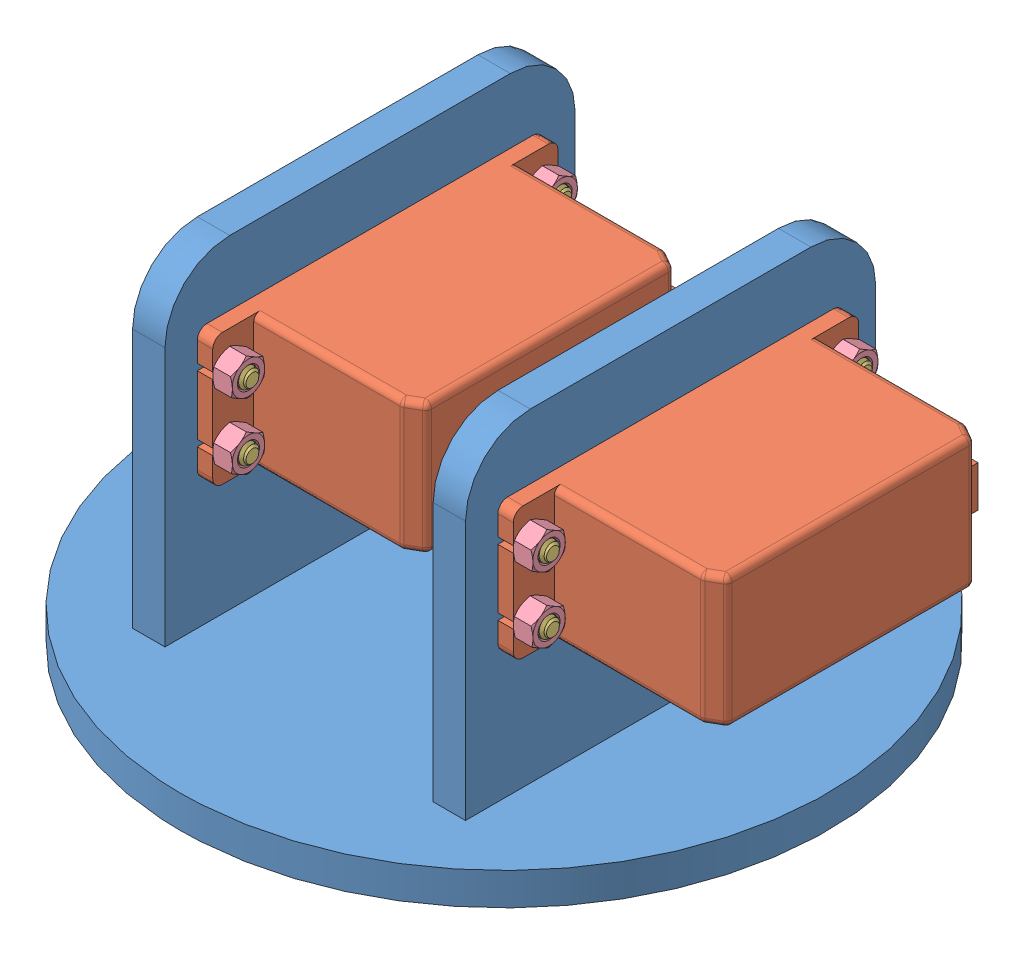
SolidWorks assembly Assem2, configuration Default. Lengths in mm.
Overall size (103.47 55 100).
19 component instances, 4 part files, 54 mates.
Components (placement in the parent):
- Part1-1: Part1 [Default] at origin size (100 55 100)
- Motor2-1: Motor2 [Default] at (-33.5143 32.34 10.1954) x (0 1 0) z (0 0 1) size (20.32 45.1 53.29)
- Motor2-2: Motor2 [Default] at (12.8743 32.34 10.1954) x (0 1 0) z (0 0 1) size (20.32 45.1 53.29)
- straf3_dolg11-1: straf3_dolg11 [Default] at (-25.6943 37.42 -24.12) x (-1 0 0) z (0 0 -1) size (14.31 5.77 5)
- straf3_dolg11-2: straf3_dolg11 [Default] at (-25.6943 27.26 -24.12) x (-1 0 0) z (0 0 -1) size (14.31 5.77 5)
- straf3_dolg11-3: straf3_dolg11 [Default] at (-25.6943 37.42 24.14) x (-1 0 0) z (0 0 -1) size (14.31 5.77 5)
- straf3_dolg11-4: straf3_dolg11 [Default] at (-25.6943 27.26 24.14) x (-1 0 0) z (0 0 -1) size (14.31 5.77 5)
- straf3_dolg11-5: straf3_dolg11 [Default] at (20.6943 27.26 -24.12) x (-1 0 0) z (0 0 -1) size (14.31 5.77 5)
- straf3_dolg11-6: straf3_dolg11 [Default] at (20.6943 37.42 -24.12) x (-1 0 0) z (0 0 -1) size (14.31 5.77 5)
- straf3_dolg11-7: straf3_dolg11 [Default] at (20.6943 27.26 24.14) x (-1 0 0) z (0 0 -1) size (14.31 5.77 5)
- straf3_dolg11-8: straf3_dolg11 [Default] at (20.6943 37.42 24.14) x (-1 0 0) z (0 0 -1) size (14.31 5.77 5)
- navrtka1-1: navrtka1 [Default] at (-16.8143 37.42 -24.12) x (0 0 -1) z (1 0 0) size (5.57 5.77 3)
- navrtka1-2: navrtka1 [Default] at (-16.8143 27.26 -24.12) x (0 0 -1) z (1 0 0) size (5.57 5.77 3)
- navrtka1-3: navrtka1 [Default] at (-16.8143 27.26 24.14) x (0 0 -1) z (1 0 0) size (5.57 5.77 3)
- navrtka1-4: navrtka1 [Default] at (-16.8143 37.42 24.14) x (0 0 -1) z (1 0 0) size (5.57 5.77 3)
- navrtka1-5: navrtka1 [Default] at (29.5743 37.42 -24.12) x (0 0 -1) z (1 0 0) size (5.57 5.77 3)
- navrtka1-6: navrtka1 [Default] at (29.5743 27.26 -24.12) x (0 0 -1) z (1 0 0) size (5.57 5.77 3)
- navrtka1-7: navrtka1 [Default] at (29.5743 37.42 24.14) x (0 0 -1) z (1 0 0) size (5.57 5.77 3)
- navrtka1-8: navrtka1 [Default] at (29.5743 27.26 24.14) x (0 0 -1) z (1 0 0) size (5.57 5.77 3)
Mates (geometry in assembly coordinates):
- Concentric1: concentric aligned: cylinder of Part1-1 through (-20.6943 27.26 -24.12) axis (1 0 0) radius 1.5; cylinder of Motor2-1 through (-20.6943 27.26 -24.12) axis (1 0 0) radius 1.5
- Concentric2: concentric aligned: cylinder of Part1-1 through (-20.6943 37.42 24.14) axis (1 0 0) radius 1.5; cylinder of Motor2-1 through (-20.6943 37.42 24.14) axis (1 0 0) radius 1.5
- Coincident1: coincident anti-aligned: plane of Part1-1 through (-20.6943 52.5 -31.65) normal (1 0 0); plane of Motor2-1 through (-20.6943 32.34 -10.15) normal (-1 0 0)
- Concentric3: concentric anti-aligned: cylinder of Part1-1 through (20.6943 27.26 -24.12) axis (-1 0 0) radius 1.5; cylinder of Motor2-2 through (25.6943 27.26 -24.12) axis (1 0 0) radius 1.5
- Concentric4: concentric anti-aligned: cylinder of Part1-1 through (20.6943 37.42 24.14) axis (-1 0 0) radius 1.5; cylinder of Motor2-2 through (25.6943 37.42 24.14) axis (1 0 0) radius 1.5
- Coincident2: coincident anti-aligned: plane of Part1-1 through (25.6943 52.5 -31.65) normal (1 0 0); plane of Motor2-2 through (25.6943 32.34 -10.15) normal (-1 0 0)
- Concentric5: concentric aligned: cylinder of Part1-1 through (-20.6943 37.42 -24.12) axis (1 0 0) radius 1.5; circle of straf3_dolg11-1
- Coincident3: coincident anti-aligned: plane of Part1-1 through (-25.6943 52.5 -31.65) normal (-1 0 0); plane of straf3_dolg11-1 through (-25.6943 37.42 -24.12) normal (1 0 0)
- Concentric6: concentric aligned: cylinder of Part1-1 through (-20.6943 27.26 -24.12) axis (1 0 0) radius 1.5; circle of straf3_dolg11-2
- Coincident4: coincident anti-aligned: plane of Part1-1 through (-25.6943 52.5 -31.65) normal (-1 0 0); plane of straf3_dolg11-2 through (-25.6943 27.26 -24.12) normal (1 0 0)
- Concentric7: concentric aligned: cylinder of Part1-1 through (-20.6943 37.42 24.14) axis (1 0 0) radius 1.5; circle of straf3_dolg11-3
- Coincident5: coincident anti-aligned: plane of Part1-1 through (-25.6943 52.5 -31.65) normal (-1 0 0); plane of straf3_dolg11-3 through (-25.6943 37.42 24.14) normal (1 0 0)
- Concentric8: concentric aligned: cylinder of Part1-1 through (-20.6943 27.26 24.14) axis (1 0 0) radius 1.5; circle of straf3_dolg11-4
- Coincident6: coincident anti-aligned: plane of Part1-1 through (-25.6943 52.5 -31.65) normal (-1 0 0); plane of straf3_dolg11-4 through (-25.6943 27.26 24.14) normal (1 0 0)
- Concentric9: concentric anti-aligned: cylinder of Part1-1 through (20.6943 27.26 -24.12) axis (-1 0 0) radius 1.5; circle of straf3_dolg11-5
- Coincident7: coincident anti-aligned: plane of Part1-1 through (20.6943 52.5 -31.65) normal (-1 0 0); plane of straf3_dolg11-5 through (20.6943 27.26 -24.12) normal (1 0 0)
- Concentric10: concentric anti-aligned: cylinder of Part1-1 through (20.6943 37.42 -24.12) axis (-1 0 0) radius 1.5; circle of straf3_dolg11-6
- Coincident8: coincident anti-aligned: plane of Part1-1 through (20.6943 52.5 -31.65) normal (-1 0 0); plane of straf3_dolg11-6 through (20.6943 37.42 -24.12) normal (1 0 0)
- Concentric12: concentric anti-aligned: cylinder of Part1-1 through (20.6943 27.26 24.14) axis (-1 0 0) radius 1.5; circle of straf3_dolg11-7
- Coincident9: coincident anti-aligned: plane of Part1-1 through (20.6943 52.5 -31.65) normal (-1 0 0); plane of straf3_dolg11-7 through (20.6943 27.26 24.14) normal (1 0 0)
- Concentric13: concentric anti-aligned: cylinder of Part1-1 through (20.6943 37.42 24.14) axis (-1 0 0) radius 1.5; circle of straf3_dolg11-8
- Coincident10: coincident anti-aligned: plane of Part1-1 through (20.6943 52.5 -31.65) normal (-1 0 0); plane of straf3_dolg11-8 through (20.6943 37.42 24.14) normal (1 0 0)
- Concentric14: concentric anti-aligned: circle of Part1-1; circle of navrtka1-1
- Coincident11: coincident anti-aligned: plane of Motor2-1 through (-18.3143 32.34 -10.15) normal (1 0 0); plane of navrtka1-1 through (-18.3143 37.42 -24.12) normal (-1 0 0)
- Concentric15: concentric anti-aligned: circle of Part1-1; circle of navrtka1-2
- Coincident12: coincident anti-aligned: plane of Motor2-1 through (-18.3143 32.34 -10.15) normal (1 0 0); plane of navrtka1-2 through (-18.3143 27.26 -24.12) normal (-1 0 0)
- Concentric16: concentric anti-aligned: circle of Part1-1; circle of navrtka1-4
- Coincident13: coincident anti-aligned: plane of Motor2-1 through (-18.3143 32.34 -10.15) normal (1 0 0); plane of navrtka1-4 through (-18.3143 37.42 24.14) normal (-1 0 0)
- Concentric17: concentric anti-aligned: circle of Part1-1; circle of navrtka1-3
- Coincident14: coincident anti-aligned: plane of Motor2-1 through (-18.3143 32.34 -10.15) normal (1 0 0); plane of navrtka1-3 through (-18.3143 27.26 24.14) normal (-1 0 0)
- Concentric18: concentric anti-aligned: circle of Part1-1; circle of navrtka1-5
- Coincident15: coincident anti-aligned: plane of Motor2-2 through (28.0743 32.34 -10.15) normal (1 0 0); plane of navrtka1-5 through (28.0743 37.42 -24.12) normal (-1 0 0)
- Concentric19: concentric anti-aligned: circle of Part1-1; circle of navrtka1-6
- Coincident16: coincident anti-aligned: plane of Motor2-2 through (28.0743 32.34 -10.15) normal (1 0 0); plane of navrtka1-6 through (28.0743 27.26 -24.12) normal (-1 0 0)
- Concentric20: concentric anti-aligned: circle of Part1-1; circle of navrtka1-7
- Coincident18: coincident anti-aligned: plane of Motor2-2 through (28.0743 32.34 -10.15) normal (1 0 0); plane of navrtka1-7 through (28.0743 37.42 24.14) normal (-1 0 0)
- Concentric21: concentric anti-aligned: circle of Part1-1; circle of navrtka1-8
- Coincident19: coincident anti-aligned: plane of Motor2-2 through (28.0743 32.34 -10.15) normal (1 0 0); plane of navrtka1-8 through (28.0743 27.26 24.14) normal (-1 0 0)
- Parallel1: parallel aligned: plane of straf3_dolg11-1; plane of assembly through (0 0 0) normal (0 1 0)
- Parallel2: parallel aligned: plane of straf3_dolg11-2; plane of assembly through (0 0 0) normal (0 1 0)
- Parallel3: parallel aligned: plane of straf3_dolg11-3; plane of assembly through (0 0 0) normal (0 1 0)
- Parallel4: parallel aligned: plane of straf3_dolg11-4; plane of assembly through (0 0 0) normal (0 1 0)
- Parallel5: parallel aligned: plane of straf3_dolg11-5; plane of assembly through (0 0 0) normal (0 1 0)
- Parallel6: parallel aligned: plane of straf3_dolg11-6; plane of assembly through (0 0 0) normal (0 1 0)
- Parallel7: parallel aligned: plane of straf3_dolg11-7; plane of assembly through (0 0 0) normal (0 1 0)
- Parallel8: parallel aligned: plane of straf3_dolg11-8; plane of assembly through (0 0 0) normal (0 1 0)
- Parallel9: parallel aligned: plane of navrtka1-1; plane of assembly through (0 0 0) normal (0 1 0)
- Parallel10: parallel aligned: plane of navrtka1-2; plane of assembly through (0 0 0) normal (0 1 0)
- Parallel11: parallel aligned: plane of navrtka1-3; plane of assembly through (0 0 0) normal (0 1 0)
- Parallel12: parallel aligned: plane of navrtka1-4; plane of assembly through (0 0 0) normal (0 1 0)
- Parallel13: parallel aligned: plane of navrtka1-5; plane of assembly through (0 0 0) normal (0 1 0)
- Parallel14: parallel aligned: plane of navrtka1-6; plane of assembly through (0 0 0) normal (0 1 0)
- Parallel15: parallel aligned: plane of navrtka1-7; plane of assembly through (0 0 0) normal (0 1 0)
- Parallel16: parallel aligned: plane of navrtka1-8; plane of assembly through (0 0 0) normal (0 1 0)
